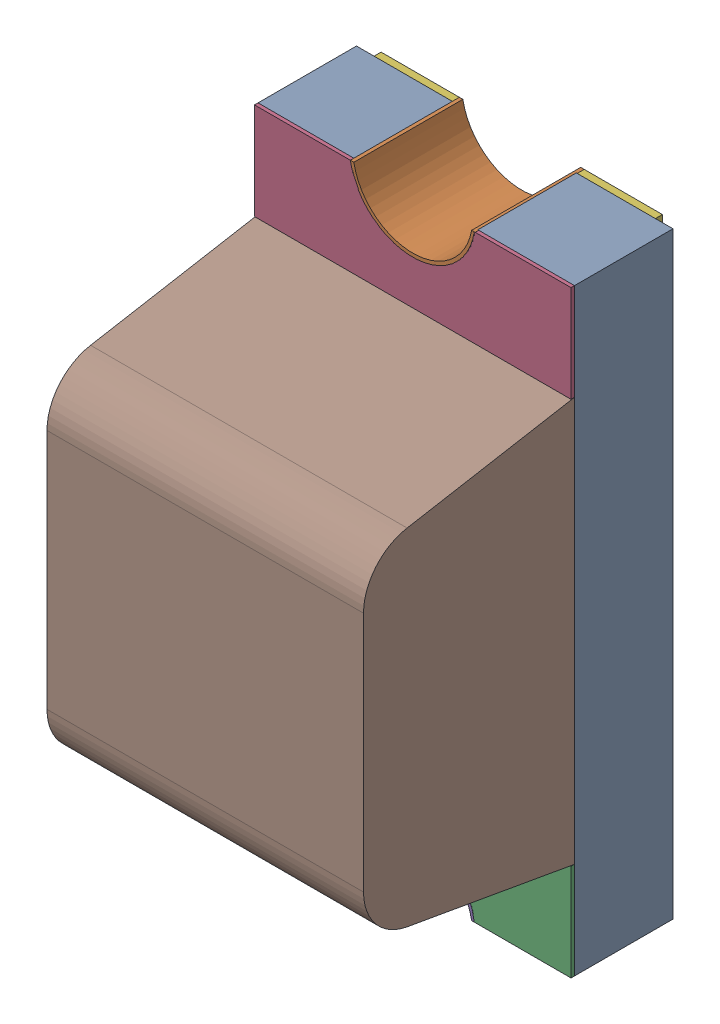
SolidWorks assembly D2K60, configuration 默认. Lengths in mm.
Overall size (0.9 1.7 0.9).
7 component instances, 6 part files, 0 mates.
Components (placement in the parent):
- LED-BLUE-0603-1: LED-BLUE-0603 [默认] at (-33.7639 17.0687 0) size (0.9 1.7 0.9)
  - User_Library-LTST-C190TBKT_Pad-1: User_Library-LTST-C190TBKT_Pad [默认] at origin size (0.9 1.7 0.28)
  - User_Library-LTST-C190TBKT_Pad005-1: User_Library-LTST-C190TBKT_Pad005 [默认] at origin size (0.35 0.15 0.31)
  - User_Library-LTST-C190TBKT_Pad001-1: User_Library-LTST-C190TBKT_Pad001 [默认] at origin size (0.9 1.7 0.01)
  - User_Library-LTST-C190TBKT_Pad004-1: User_Library-LTST-C190TBKT_Pad004 [默认] at origin size (0.35 0.15 0.31)
  - User_Library-LTST-C190TBKT_Pad003-1: User_Library-LTST-C190TBKT_Pad003 [默认] at origin size (0.8 1.7 0.02)
  - User_Library-LTST-C190TBKT_Lens-1: User_Library-LTST-C190TBKT_Lens [默认] at origin size (0.9 1.15 0.6)
